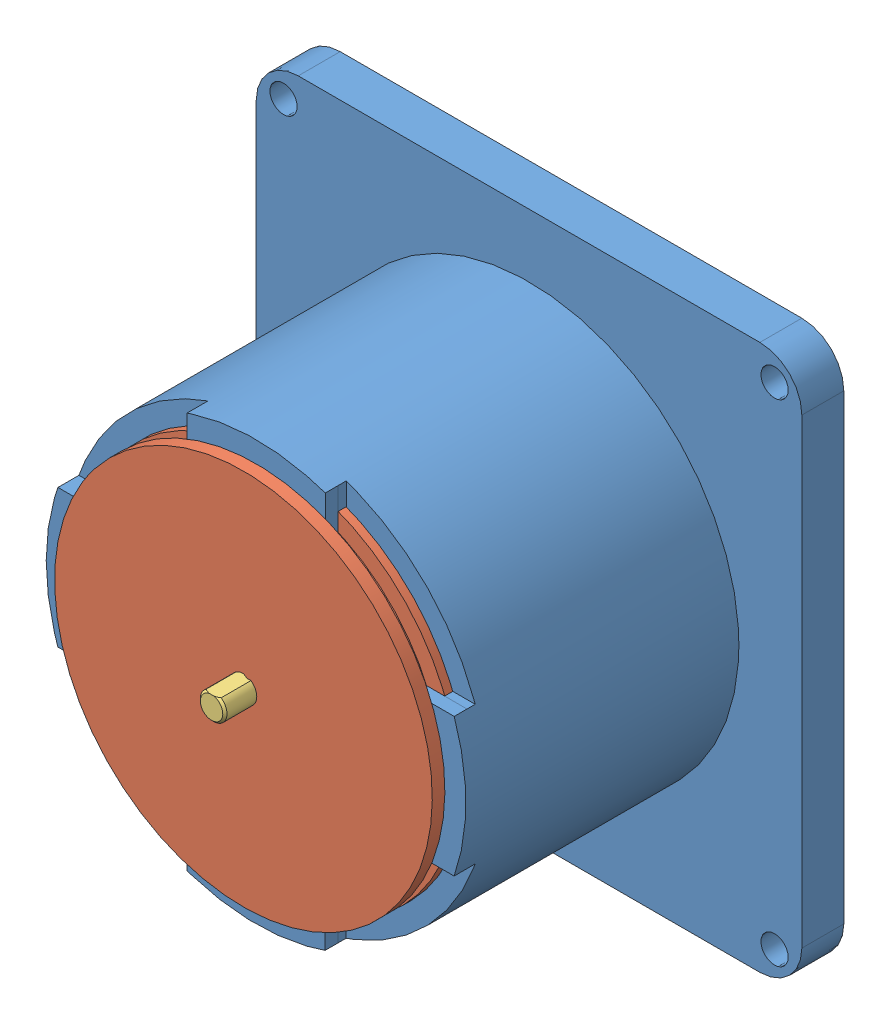
SolidWorks assembly Złożenie1, configuration Domyślna. Lengths in mm.
Overall size (130 130 85.65).
5 component instances, 4 part files, 4 mates.
Components (placement in the parent):
- Podstawa-1: Podstawa [Domyślna] at (-12.9472 5.5241 130) size (130 130 75.05)
- talerz do podstawy-1: talerz do podstawy [Domyślna] at (-12.9472 5.5241 208.05) x (-0.82309 0.567911 0) z (0 0 -1) size (90 90 8.6)
- 57cm12x-1: 57cm12x [Default] at (-12.9472 5.5241 185.05) size (57.15 58.15 75.6)
  - 57cm12x_01-1: 57cm12x_01 [Default] at origin size (6.35 6.35 19)
  - 57cm12x_02-1: 57cm12x_02 [Default] at origin size (57.15 58.15 56.6)
Mates (geometry in assembly coordinates):
- Wspólnie1: coincident anti-aligned: plane of Podstawa-1 through (-12.9472 5.5241 195.05) normal (0 0 -1); plane of 57cm12x-1/57cm12x_02-1 through (15.6278 34.0991 195.05) normal (0 0 1)
- Koncentryczne1: concentric aligned: circle of Podstawa-1; circle of 57cm12x-1/57cm12x_02-1
- Koncentryczne2: concentric anti-aligned: circle of Podstawa-1; circle of talerz do podstawy-1
- Wspólnie3: coincident anti-aligned: plane of Podstawa-1 through (-12.9472 5.5241 205.05) normal (0 0 1); plane of talerz do podstawy-1 through (-12.9472 5.5241 205.05) normal (0 0 -1)
